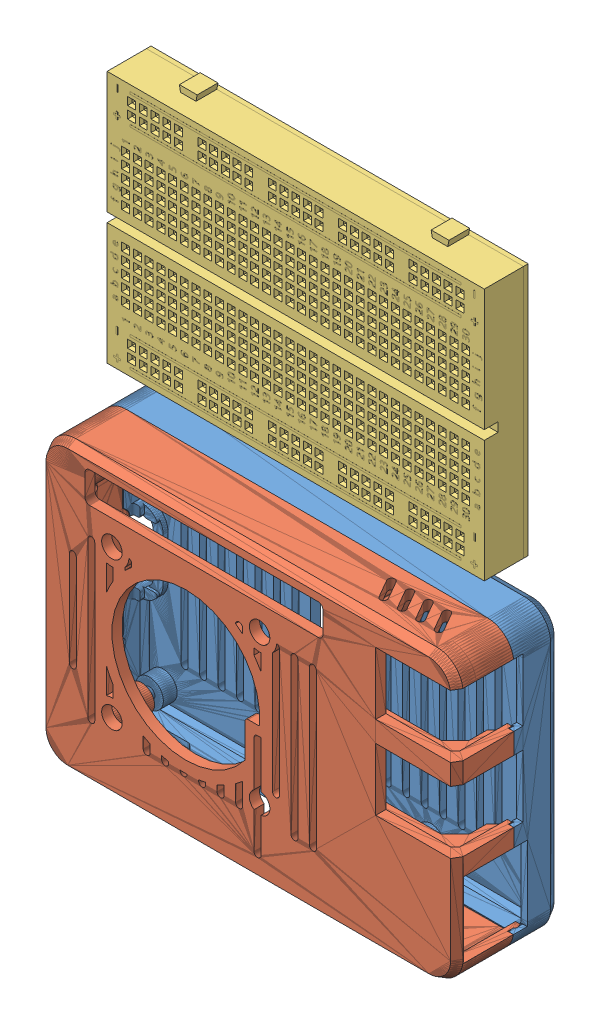
SolidWorks assembly Raspberry Pi Assembly, configuration Default. Lengths in mm.
Overall size (89.6 123.84 22.4).
3 component instances, 3 part files, 9 mates.
Components (placement in the parent):
- Pi Bottom-1: Pi Bottom [Default] at (45.2 -58.7 5.2) size (89.6 61.4 9.7)
- Pi Top-1: Pi Top [Default] at (45.2 -58.7 5.2) x (-1 0 0) z (0 0 -1) size (89.6 61.4 16.85)
- HalfBreadboard-1: HalfBreadboard [Default] at (42.17 75.6484 5.25) x (0 1 0) z (1 0 0) size (56.08 9.51 83.01)
Mates (geometry in assembly coordinates):
- Coincident2: coincident anti-aligned: plane of Pi Bottom-1 through (45.2 -58.7 0) normal (0 0 -1)
- Coincident3: coincident aligned: plane of Pi Bottom-1 through (45.2 0 5.2) normal (0 1 0)
- Coincident4: coincident anti-aligned: plane of Pi Bottom-1 through (0 -58.7 5.2) normal (-1 0 0)
- Concentric1: concentric anti-aligned: circle of Pi Bottom-1; circle of Pi Top-1
- Concentric2: concentric anti-aligned: circle of Pi Bottom-1; circle of Pi Top-1
- Coincident5: coincident anti-aligned: plane of Pi Bottom-1 through (45.2 -58.7 9.7) normal (0 0 1); plane of Pi Top-1 through (45.2 -58.7 9.7) normal (0 0 -1)
- Coincident6: coincident aligned: plane of Pi Bottom-1 through (45.2 -58.7 0) normal (0 0 -1); plane of HalfBreadboard-1 through (0.26 33.7384 0) normal (0 0 -1)
- Parallel1: parallel anti-aligned: plane of Pi Bottom-1 through (45.2 0 5.2) normal (0 1 0); plane of HalfBreadboard-1 through (83.01 6.3634 9.5) normal (0 -1 0)
- Coincident11: coincident aligned: plane of Pi Bottom-1 through (0 -58.7 5.2) normal (-1 0 0); plane of HalfBreadboard-1 through (0 75.6484 5.5) normal (-1 0 0)
